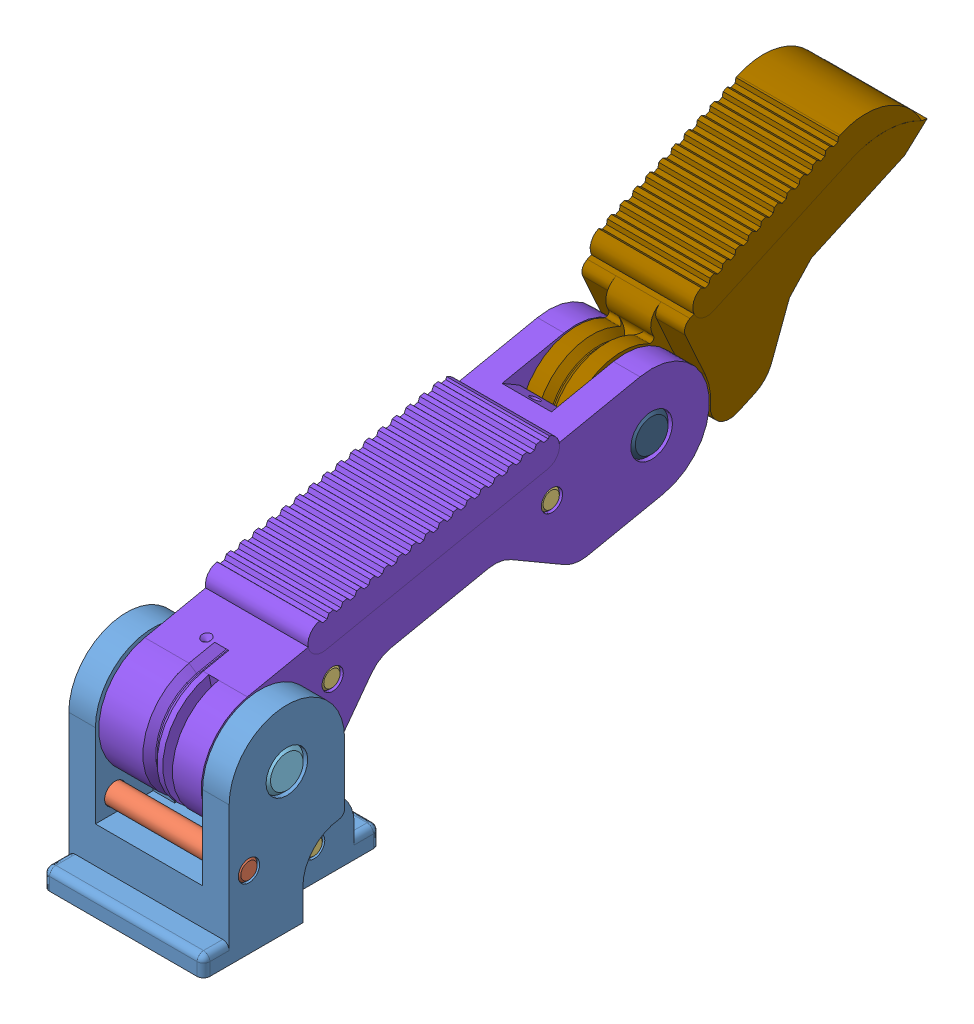
SolidWorks assembly block_finger_pp_t, configuration Default. Lengths in mm.
Overall size (25.4 64.31 122.72).
16 component instances, 10 part files, 30 mates.
Components (placement in the parent):
- c1_t-1: c1_t [Default] at origin size (25 30.67 32)
- 98381A475 D1-8 L1-1: 98381A475 D1-8 L1 [98381A475] at (-0.2 11.2575 -8.8732) size (25.4 3.17 3.17)
- 98381A472 D1-8 L5-8-3: 98381A472 D1-8 L5-8 [98381A472] at (0.0625 4.925 -23.535) size (15.88 3.17 3.17)
- 3434T31 - nylon pulley-1: 3434T31 - nylon pulley [Default] at (-0.15 4.925 -23.535) x (0 -1 0) z (0 0 1) size (9.5 2.4 9.5)
- 98381A472 D1-8 L5-8-1: 98381A472 D1-8 L5-8 [98381A472] at (0.0875 26.2418 -26.2751) size (15.88 3.17 3.17)
- 98381A472 D1-8 L5-8-2: 98381A472 D1-8 L5-8 [98381A472] at (0.0875 33.276 -60.462) size (15.88 3.17 3.17)
- 98381A542 D1-4 L1-1: 98381A542 D1-4 L1 [98381A542] at (-0.2 21.67 -14.7858) size (25.4 6.35 6.35)
- 93365A120 4-40 insert-1: 93365A120 4-40 insert [93365A120] at (0 43.7875 -99.345) x (1 0 0) z (0 0.729761 -0.683703) size (4.37 3.82 4.37)
- 91253A106 4-40 L1-4 countersunk-1: 91253A106 4-40 L1-4 countersunk [91253A106] at (0 42.3372 -100.893) x (1 0 0) z (0 -0.683703 -0.729761) size (6.48 6.48 6.63)
- t_pp_A-1: t_pp_A [Default] at (0.15 21.67 -14.7858) x (1 0 0) z (0 -0.201536 0.979481) size (16 20.25 80.5)
- t_pp_B-1: t_pp_B [Default] at (0 34.266 -76.0033) x (1 0 0) z (0 -0.412569 0.910926) size (16 22.88 57.08)
- 98381A539 D1-4 L5-8-1: 98381A539 D1-4 L5-8 [98381A539] at (0.2125 34.266 -76.0033) size (15.88 6.35 6.35)
- 93365A120 4-40 insert-2: 93365A120 4-40 insert [93365A120] at (0 28.2944 -84.633) x (1 0 0) z (0 0.412569 -0.910926) size (4.37 3.82 4.37)
- 93365A120 4-40 insert-3: 93365A120 4-40 insert [93365A120] at (0.15 23.133 -66.5531) x (-0.837169 0.110229 -0.535721) z (-0.546944 -0.16872 0.819991) size (4.37 3.82 4.37)
- 91253A106 4-40 L1-4 countersunk-2: 91253A106 4-40 L1-4 countersunk [91253A106] at (0 26.3622 -85.5081) x (1 0 0) z (0 -0.910926 -0.412569) size (6.48 6.48 6.63)
- 91253A106 4-40 L1-4 countersunk-3: 91253A106 4-40 L1-4 countersunk [91253A106] at (0.15 21.0553 -66.9806) x (1 0 0) z (0 -0.979481 -0.201536) size (6.48 6.48 6.63)
Mates (geometry in assembly coordinates):
- Concentric1: concentric: cylinder of c1_t-1 through (-12.5 21.67 -14.7858) axis (1 0 0) radius 3.25; cylinder of 98381A542 D1-4 L1-1 through (-12.9 21.67 -14.7858) axis (1 0 0) radius 3.175
- Coincident1: coincident: plane of c1_t-1 through (12.5 21.67 -14.7858) normal (1 0 0); plane of 98381A542 D1-4 L1-1 through (12.5 21.67 -14.7858) normal (1 0 0)
- Concentric5: concentric: cylinder of c1_t-1 through (-12.5 4.925 -23.535) axis (1 0 0) radius 1.6625; cylinder of 98381A472 D1-8 L5-8-3 through (-7.875 4.925 -23.535) axis (1 0 0) radius 1.5875
- Coincident5: coincident: plane of c1_t-1 through (8 4.925 -23.535) normal (1 0 0); plane of 98381A472 D1-8 L5-8-3 through (8 4.925 -23.535) normal (1 0 0)
- Concentric6: concentric: cylinder of c1_t-1 through (-12.5 11.2575 -8.8732) axis (1 0 0) radius 1.6625; cylinder of 98381A475 D1-8 L1-1 through (-12.9 11.2575 -8.8732) axis (1 0 0) radius 1.5875
- Coincident6: coincident: plane of c1_t-1 through (12.5 21.67 -14.7858) normal (1 0 0); plane of 98381A475 D1-8 L1-1 through (12.5 11.2575 -8.8732) normal (1 0 0)
- Concentric8: concentric: circle of 93365A120 4-40 insert-1; circle of 91253A106 4-40 L1-4 countersunk-1
- Coincident8: coincident: circle of 93365A120 4-40 insert-1; cone of 91253A106 4-40 L1-4 countersunk-1 through (0 43.7786 -99.3545) axis (0 0.683703 0.729761)
- Concentric9: concentric: cylinder of 98381A542 D1-4 L1-1 through (-12.9 21.67 -14.7858) axis (1 0 0) radius 3.175; cylinder of t_pp_A-1 through (-7.85 21.67 -14.7858) axis (1 0 0) radius 3.525
- Distance2: distance = 0.2 mm: plane of t_pp_A-1 through (8.15 21.67 -14.7858) normal (1 0 0); plane of c1_t-1 through (8.35 21.67 -14.7858) normal (-1 0 0)
- Concentric10: concentric: cylinder of 98381A472 D1-8 L5-8-1 through (-7.85 26.2418 -26.2751) axis (1 0 0) radius 1.5875; cylinder of t_pp_A-1 through (-7.85 26.2418 -26.2751) axis (1 0 0) radius 1.6625
- Coincident10: coincident: plane of 98381A472 D1-8 L5-8-1 through (-7.85 26.2418 -26.2751) normal (-1 0 0); plane of t_pp_A-1 through (-7.85 21.67 -14.7858) normal (-1 0 0)
- Concentric11: concentric: cylinder of 98381A472 D1-8 L5-8-2 through (-7.85 33.276 -60.462) axis (1 0 0) radius 1.5875; cylinder of t_pp_A-1 through (-7.85 33.276 -60.462) axis (1 0 0) radius 1.6625
- Coincident11: coincident: plane of 98381A472 D1-8 L5-8-2 through (-7.85 33.276 -60.462) normal (-1 0 0); plane of t_pp_A-1 through (-7.85 21.67 -14.7858) normal (-1 0 0)
- Concentric12: concentric: circle of 93365A120 4-40 insert-1; cylinder of t_pp_B-1 through (0 46.8641 -96.0611) axis (0 -0.683703 -0.729761) radius 1.85
- Coincident12: coincident: plane of 93365A120 4-40 insert-1 through (0 43.7875 -99.345) normal (0 -0.683703 -0.729761); plane of t_pp_B-1 through (-13 45.6119 -101.0543) normal (0 -0.683703 -0.729761)
- Concentric13: concentric: cylinder of t_pp_A-1 through (-7.85 34.266 -76.0033) axis (1 0 0) radius 3.25; cylinder of t_pp_B-1 through (-8 34.266 -76.0033) axis (1 0 0) radius 3.525
- Distance3: distance = 0.2 mm: plane of t_pp_B-1 through (-3.5 34.266 -76.0033) normal (-1 0 0); plane of t_pp_A-1 through (-3.7 34.266 -76.0033) normal (1 0 0)
- Concentric14: concentric: cylinder of t_pp_B-1 through (-8 34.266 -76.0033) axis (1 0 0) radius 3.525; cylinder of 98381A539 D1-4 L5-8-1 through (-7.725 34.266 -76.0033) axis (1 0 0) radius 3.175
- Coincident14: coincident: plane of t_pp_A-1 through (8.15 21.67 -14.7858) normal (1 0 0); plane of 98381A539 D1-4 L5-8-1 through (8.15 34.266 -76.0033) normal (1 0 0)
- Concentric15: concentric: cylinder of 98381A472 D1-8 L5-8-3 through (-7.875 4.925 -23.535) axis (1 0 0) radius 1.5875; cylinder of 3434T31 - nylon pulley-1 through (-0.15 4.925 -23.535) axis (-1 0 0) radius 1.5
- Distance4: distance = 0.2 mm: plane of 3434T31 - nylon pulley-1 through (-1.35 3.425 -23.535) normal (-1 0 0); plane of c1_t-1 through (-1.55 4.925 -23.535) normal (1 0 0)
- Concentric16: concentric: cylinder of t_pp_A-1 through (0.15 27.5407 -65.6462) axis (0 -0.979481 -0.201536) radius 1.85; circle of 93365A120 4-40 insert-3
- Coincident16: coincident: plane of t_pp_A-1 through (8.15 12.8546 -16.5996) normal (0 -0.979481 -0.201536); plane of 93365A120 4-40 insert-3 through (0.15 23.133 -66.5531) normal (0 -0.979481 -0.201536)
- Concentric17: concentric: cylinder of t_pp_B-1 through (0 31.9381 -82.9827) axis (0 -0.910926 -0.412569) radius 1.85; circle of 93365A120 4-40 insert-2
- Coincident17: coincident: plane of t_pp_B-1 through (8 26.0677 -79.7164) normal (0 -0.910926 -0.412569); plane of 93365A120 4-40 insert-2 through (0 28.2944 -84.633) normal (0 -0.910926 -0.412569)
- Concentric18: concentric: circle of t_pp_B-1; circle of 91253A106 4-40 L1-4 countersunk-2
- Coincident18: coincident: circle of 93365A120 4-40 insert-2; cone of 91253A106 4-40 L1-4 countersunk-2 through (0 28.2826 -84.6383) axis (0 0.910926 0.412569)
- Concentric19: concentric: circle of 93365A120 4-40 insert-3; circle of 91253A106 4-40 L1-4 countersunk-3
- Coincident19: coincident: circle of 93365A120 4-40 insert-3; cone of 91253A106 4-40 L1-4 countersunk-3 through (0.15 23.1203 -66.5557) axis (0 0.979481 0.201536)
